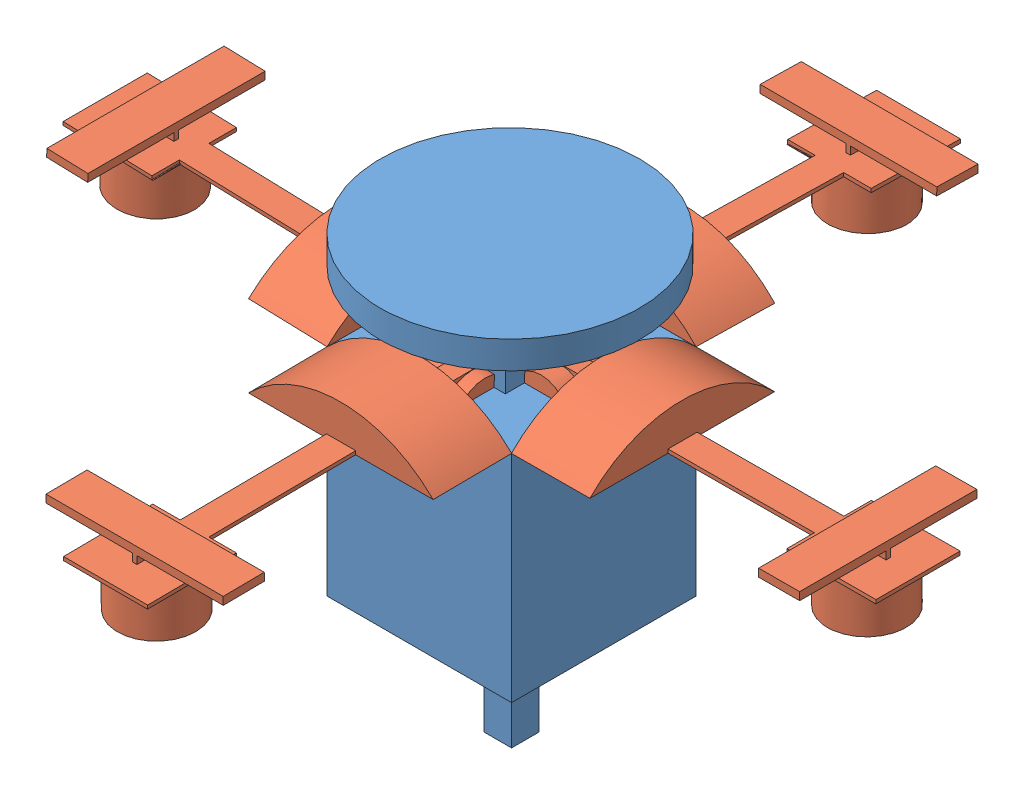
SolidWorks assembly Assemrotated, configuration Default. Lengths in mm.
Overall size (207.43 110 207.37).
5 component instances, 2 part files, 7 mates.
Components (placement in the parent):
- Part1-1: Part1 [Default] at (13.7374 -0.6868 112.0514) size (66 110 66)
- Part2-1: Part2 [Default] at (80.8445 61.2586 88.5714) x (-0.004633 0.999141 -0.041185) z (-0.000191 0.041184 0.999152) size (22.27 97.36 47)
- Part2-2: Part2 [Default] at (37.2574 60.9793 131.8338) x (0.041185 0.999108 0.009357) z (-0.999152 0.041183 0.000386) size (22.27 97.36 47)
- Part2-3: Part2 [Default] at (-6.9606 61.7876 88.5315) x (0.030534 0.998685 0.041185) z (0.001259 0.041166 -0.999152) size (22.27 97.36 47)
- Part2-6: Part2 [Default] at (37.2707 60.8118 45.4046) x (-0.041136 0.998992 -0.017971) z (0.99915 0.041178 0.001974) size (22.27 97.36 47)
Mates (geometry in assembly coordinates):
- Coincident2: coincident anti-aligned: line of Part1-1 through (60.7374 84.3132 112.0514) axis (0 0 -1); line of Part2-1 through (60.7374 84.3132 65.0514) axis (0 0 1)
- Coincident3: coincident: line of Part1-1 through (60.7374 84.3132 65.0514) axis (-1 0 0); point of Part2-1
- Coincident5: coincident anti-aligned: line of Part1-1 through (13.7374 84.3132 112.0514) axis (1 0 0); line of Part2-2 through (60.7773 84.3132 112.0514) axis (-1 0 0)
- Coincident6: coincident: line of Part1-1 through (13.7374 84.3132 65.0514) axis (0 0 1); point of Part2-2
- Coincident14: coincident: point of Part1-1; point of Part2-3
- Coincident17: coincident anti-aligned: line of Part1-1 through (13.7374 84.3132 65.0514) axis (0 0 1); line of Part2-3 through (13.7374 84.3132 112.0514) axis (0 0 -1)
- Coincident34: coincident: point of Part1-1; point of Part2-6
